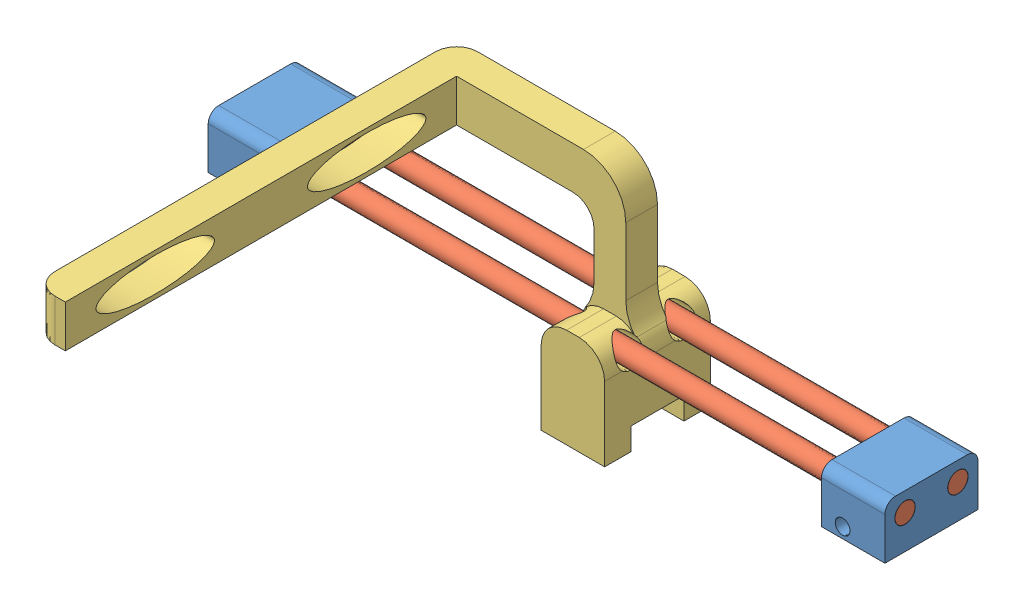
SolidWorks assembly Straight Pusher subassembly 3, configuration Default. Lengths in mm.
Overall size (160 53.75 108.75).
5 component instances, 3 part files, 10 mates.
Components (placement in the parent):
- Dowel Holder (003)-1: Dowel Holder (003) [Default] at (-72.4718 -40.6088 -8.4569) x (0 0 -1) z (1 0 0) size (22 12.5 15)
- Dowel Holder (003)-2: Dowel Holder (003) [Default] at (87.5282 -40.6088 -8.4569) x (0 0 1) z (-1 0 0) size (22 12.5 15)
- dowel-1: dowel [Default] at (-72.4718 -20.1088 -2.2069) size (160 4.75 4.75)
- dowel-2: dowel [Default] at (-72.4718 -20.1088 -14.7069) size (160 4.75 4.75)
- S2_Pusher Piece Top-1: S2_Pusher Piece Top [Default] at (7.7549 29.3686 38.21) x (0 0 -1) z (1 0 0) size (108.75 53.75 51.25)
Mates (geometry in assembly coordinates):
- Concentric1: concentric anti-aligned: cylinder of Dowel Holder (003)-2 through (72.5282 -20.1088 -14.7069) axis (1 0 0) radius 2.425; cylinder of dowel-2 through (87.5282 -20.1088 -14.7069) axis (-1 0 0) radius 2.375
- Concentric2: concentric aligned: cylinder of Dowel Holder (003)-1 through (-57.4718 -20.1088 -14.7069) axis (-1 0 0) radius 2.425; cylinder of dowel-2 through (87.5282 -20.1088 -14.7069) axis (-1 0 0) radius 2.375
- Concentric3: concentric anti-aligned: cylinder of Dowel Holder (003)-2 through (72.5282 -20.1088 -2.2069) axis (1 0 0) radius 2.425; cylinder of dowel-1 through (87.5282 -20.1088 -2.2069) axis (-1 0 0) radius 2.375
- Concentric4: concentric aligned: cylinder of Dowel Holder (003)-1 through (-57.4718 -20.1088 -2.2069) axis (-1 0 0) radius 2.425; cylinder of dowel-1 through (87.5282 -20.1088 -2.2069) axis (-1 0 0) radius 2.375
- Coincident1: coincident aligned: plane of Dowel Holder (003)-2 through (87.5282 -40.6088 -8.4569) normal (1 0 0); plane of dowel-1 through (87.5282 -20.1088 -2.2069) normal (1 0 0)
- Coincident2: coincident aligned: plane of Dowel Holder (003)-2 through (87.5282 -40.6088 -8.4569) normal (1 0 0); plane of dowel-2 through (87.5282 -20.1088 -14.7069) normal (1 0 0)
- Coincident3: coincident aligned: plane of Dowel Holder (003)-1 through (-72.4718 -40.6088 -8.4569) normal (-1 0 0); plane of dowel-2 through (-72.4718 -20.1088 -14.7069) normal (-1 0 0)
- Coincident4: coincident aligned: plane of Dowel Holder (003)-1 through (-72.4718 -40.6088 -8.4569) normal (-1 0 0); plane of dowel-1 through (-72.4718 -20.1088 -2.2069) normal (-1 0 0)
- Concentric5: concentric aligned: cylinder of dowel-1 through (87.5282 -20.1088 -2.2069) axis (-1 0 0) radius 2.375; cylinder of S2_Pusher Piece Top-1 through (22.7549 -20.1088 -2.2069) axis (-1 0 0) radius 3.175
- Concentric6: concentric aligned: cylinder of dowel-2 through (87.5282 -20.1088 -14.7069) axis (-1 0 0) radius 2.375; cylinder of S2_Pusher Piece Top-1 through (22.7549 -20.1088 -14.7069) axis (-1 0 0) radius 3.175
